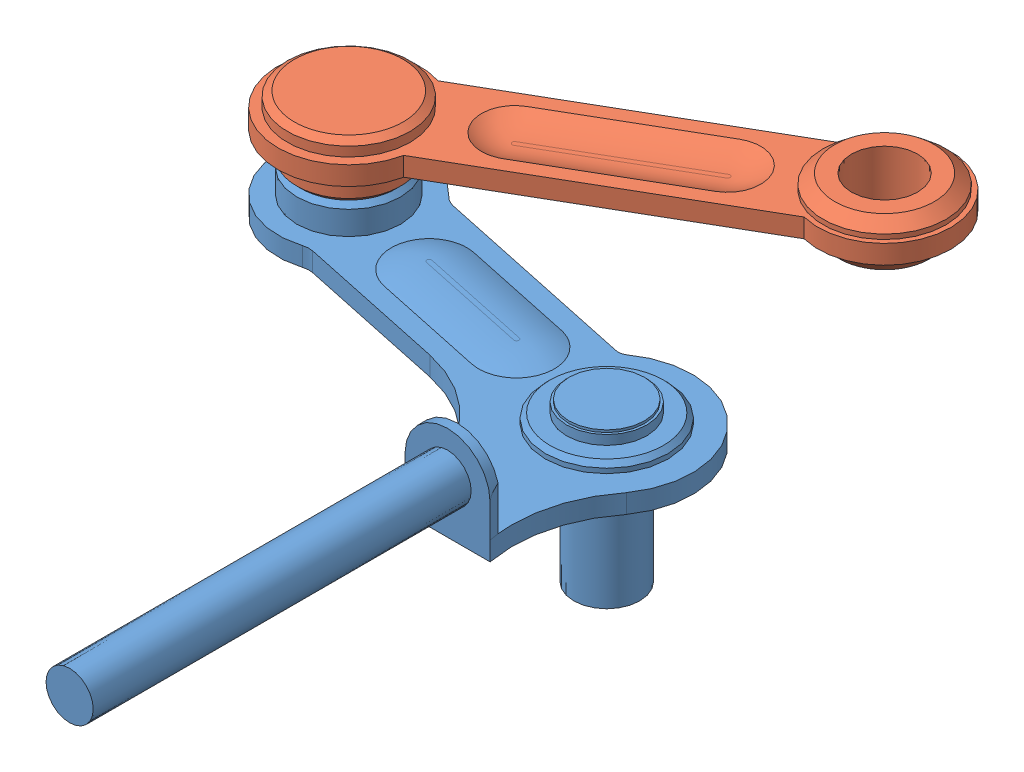
SolidWorks assembly larga, configuration Predeterminado. Lengths in mm.
Overall size (55.98 24 95.01).
2 component instances, 2 part files, 2 mates.
Components (placement in the parent):
- larga-1: larga [Predeterminado] at (21.2652 1.9894 71.7169) size (51.24 22.5 71.72)
- larga2-1: larga2 [Predeterminado] at (-4.9825 9.9894 52.5975) x (0.865389 0 -0.5011) z (0.5011 0 0.865389) size (56 13 15)
Mates (geometry in assembly coordinates):
- Concéntrica1: concentric aligned: cylinder of larga-1 through (-28.889 1.9697 63.5472) axis (0 1 0) radius 2.5; cylinder of larga2-1 through (-28.889 0.4894 63.5472) axis (0 1 0) radius 2.5
- Coincidente1: coincident anti-aligned: plane of larga-1 through (-28.889 6.9894 63.5472) normal (0 1 0); circle of larga2-1
